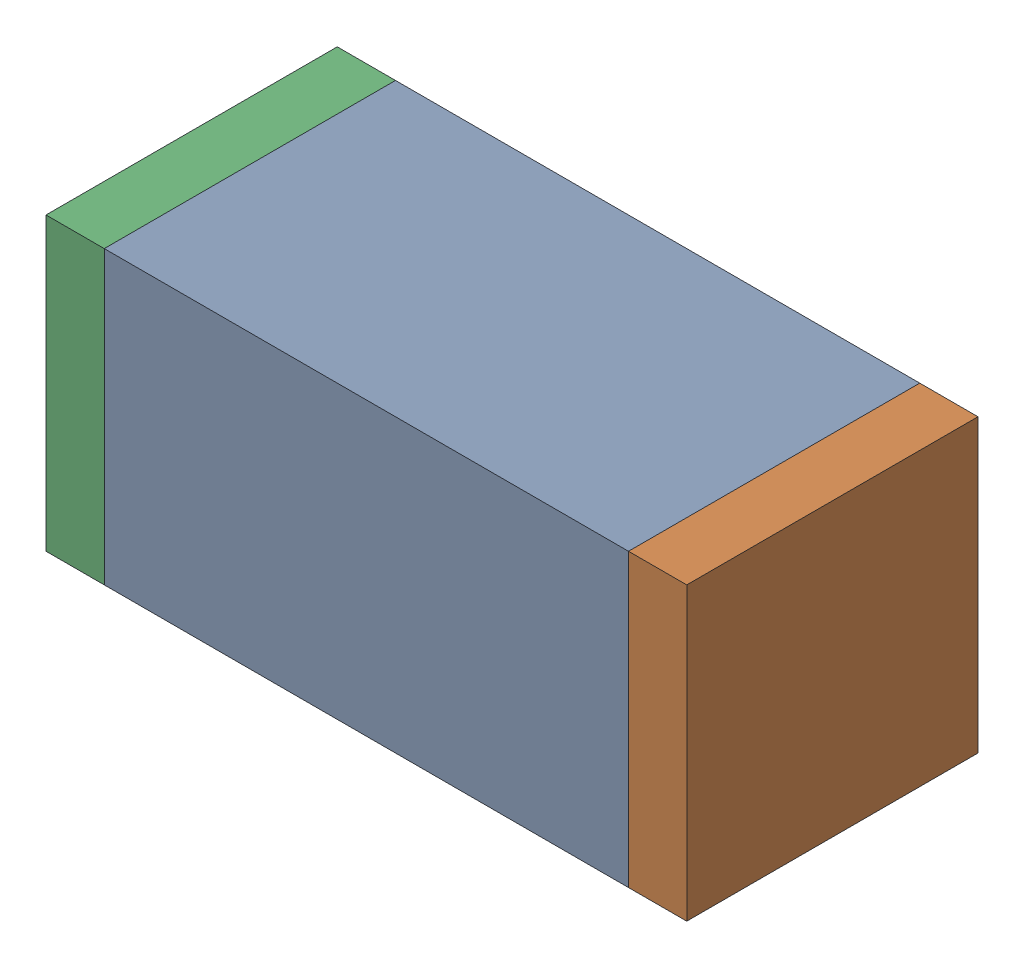
SolidWorks assembly C10, configuration Default. Lengths in mm.
Overall size (1.1 0.5 0.5).
6 component instances, 2 part files, 0 mates.
Components (placement in the parent):
- 836749680-1: 836749680 [Default] at (127.9 9.45 0) size (0.9 0.5 0.5)
  - Extruded_4-1: Extruded_4 [Default] at origin size (0.9 0.5 0.5)
- 810156080-1: 810156080 [Default] at (128.4 9.45 0) size (0.1 0.5 0.5)
  - Extruded_5-1: Extruded_5 [Default] at origin size (0.1 0.5 0.5)
- 810156080-2: 810156080 [Default] at (127.4 9.45 0) size (0.1 0.5 0.5)
  - Extruded_5-1: Extruded_5 [Default] at origin size (0.1 0.5 0.5)
